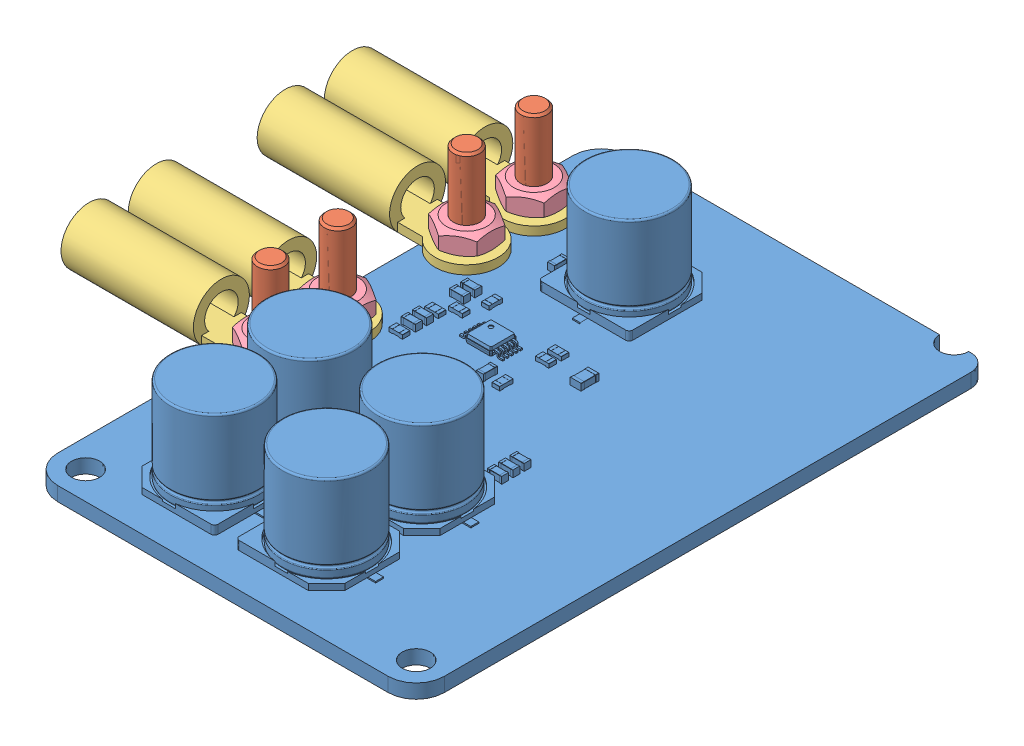
SolidWorks assembly Boost-Converter, configuration Standard. Lengths in mm.
Overall size (61.21 15.1 64.77).
13 component instances, 4 part files, 39 mates.
Components (placement in the parent):
- lt3757-boost-converter-1: lt3757-boost-converter [Standard] x (1 0 0) z (0 1 0) size (43.81 64.77 12.1)
- b-DIN EN ISO 4762-M3x12-1: b-DIN EN ISO 4762-M3x12 [Default] at (-18.7325 -1.6 -21.59) x (1 0 0) z (0 -1 0) size (5.5 5.5 15)
- b-DIN EN ISO 4762-M3x12-2: b-DIN EN ISO 4762-M3x12 [Default] at (-18.7325 -1.6 -13.97) x (1 0 0) z (0 -1 0) size (5.5 5.5 15)
- b-DIN EN ISO 4762-M3x12-3: b-DIN EN ISO 4762-M3x12 [Default] at (-18.7325 -1.6 0.635) x (1 0 0) z (0 -1 0) size (5.5 5.5 15)
- b-DIN EN ISO 4762-M3x12-4: b-DIN EN ISO 4762-M3x12 [Default] at (-18.7325 -1.6 8.255) x (1 0 0) z (0 -1 0) size (5.5 5.5 15)
- Cable-Lug_TE-2-34852-1-1: Cable-Lug_TE-2-34852-1 [Standard] at (-18.7325 0 -21.59) x (-1 0 0) z (0 0 -1) size (24.14 6.35 7.14)
- Cable-Lug_TE-2-34852-1-2: Cable-Lug_TE-2-34852-1 [Standard] at (-18.7325 0 -13.97) x (-1 0 0) z (0 0 -1) size (24.14 6.35 7.14)
- Cable-Lug_TE-2-34852-1-3: Cable-Lug_TE-2-34852-1 [Standard] at (-18.7325 0 0.635) x (-1 0 0) z (0 0 -1) size (24.14 6.35 7.14)
- Cable-Lug_TE-2-34852-1-4: Cable-Lug_TE-2-34852-1 [Standard] at (-18.7325 0 8.255) x (-1 0 0) z (0 0 -1) size (24.14 6.35 7.14)
- b-DIN EN ISO 4032-M3-1: b-DIN EN ISO 4032-M3 [Default] at (-18.7325 0.99 -21.59) x (0.866025 0 -0.5) z (0 1 0) size (6.35 5.5 2.4)
- b-DIN EN ISO 4032-M3-2: b-DIN EN ISO 4032-M3 [Default] at (-18.7325 0.99 -13.97) x (0.866025 0 -0.5) z (0 1 0) size (6.35 5.5 2.4)
- b-DIN EN ISO 4032-M3-3: b-DIN EN ISO 4032-M3 [Default] at (-18.7325 0.99 0.635) x (0.866025 0 -0.5) z (0 1 0) size (6.35 5.5 2.4)
- b-DIN EN ISO 4032-M3-4: b-DIN EN ISO 4032-M3 [Default] at (-18.7325 0.99 8.255) x (0.866025 0 -0.5) z (0 1 0) size (6.35 5.5 2.4)
Mates (geometry in assembly coordinates):
- Konzentrisch1: concentric anti-aligned: cylinder of lt3757-boost-converter-1 through (-18.7325 0 -21.59) axis (0 1 0) radius 1.6; cylinder of b-DIN EN ISO 4762-M3x12-1 through (-18.7325 -6.2001 -21.59) axis (0 -1 0) radius 1.5
- Konzentrisch2: concentric anti-aligned: cylinder of lt3757-boost-converter-1 through (-18.7325 0 -13.97) axis (0 1 0) radius 1.6; cylinder of b-DIN EN ISO 4762-M3x12-2 through (-18.7325 -6.2001 -13.97) axis (0 -1 0) radius 1.5
- Konzentrisch3: concentric anti-aligned: cylinder of lt3757-boost-converter-1 through (-18.7325 0 0.635) axis (0 1 0) radius 1.6; cylinder of b-DIN EN ISO 4762-M3x12-3 through (-18.7325 -6.2001 0.635) axis (0 -1 0) radius 1.5
- Konzentrisch4: concentric anti-aligned: cylinder of lt3757-boost-converter-1 through (-18.7325 0 8.255) axis (0 1 0) radius 1.6; cylinder of b-DIN EN ISO 4762-M3x12-4 through (-18.7325 -6.2001 8.255) axis (0 -1 0) radius 1.5
- Deckungsgleich2: coincident anti-aligned: plane of lt3757-boost-converter-1 through (21.9075 -1.6 -30.48) normal (0 -1 0); plane of b-DIN EN ISO 4762-M3x12-1 through (-18.7325 -1.6 -18.84) normal (0 1 0)
- Deckungsgleich3: coincident anti-aligned: plane of lt3757-boost-converter-1 through (21.9075 -1.6 -30.48) normal (0 -1 0); plane of b-DIN EN ISO 4762-M3x12-2 through (-18.7325 -1.6 -11.22) normal (0 1 0)
- Deckungsgleich4: coincident anti-aligned: plane of lt3757-boost-converter-1 through (21.9075 -1.6 -30.48) normal (0 -1 0); plane of b-DIN EN ISO 4762-M3x12-3 through (-18.7325 -1.6 3.385) normal (0 1 0)
- Deckungsgleich5: coincident anti-aligned: plane of lt3757-boost-converter-1 through (21.9075 -1.6 -30.48) normal (0 -1 0); plane of b-DIN EN ISO 4762-M3x12-4 through (-18.7325 -1.6 11.005) normal (0 1 0)
- Parallel1: parallel aligned: plane of b-DIN EN ISO 4762-M3x12-1; plane of b-DIN EN ISO 4762-M3x12-2
- Parallel2: parallel aligned: plane of b-DIN EN ISO 4762-M3x12-1; plane of b-DIN EN ISO 4762-M3x12-3
- Parallel3: parallel aligned: plane of b-DIN EN ISO 4762-M3x12-1; plane of b-DIN EN ISO 4762-M3x12-4
- Parallel4: parallel anti-aligned: plane of b-DIN EN ISO 4762-M3x12-1; plane of lt3757-boost-converter-1 through (-21.9075 0 -29.21) normal (-1 0 0)
- Konzentrisch5: concentric aligned: cylinder of b-DIN EN ISO 4762-M3x12-4 through (-18.7325 -6.2001 8.255) axis (0 -1 0) radius 1.5; cylinder of Cable-Lug_TE-2-34852-1-4 through (-18.7325 0.99 8.255) axis (0 -1 0) radius 1.84
- Konzentrisch6: concentric anti-aligned: cylinder of b-DIN EN ISO 4762-M3x12-3 through (-18.7325 -6.2001 0.635) axis (0 -1 0) radius 1.5; circle of Cable-Lug_TE-2-34852-1-3
- Konzentrisch7: concentric aligned: cylinder of b-DIN EN ISO 4762-M3x12-2 through (-18.7325 -6.2001 -13.97) axis (0 -1 0) radius 1.5; cylinder of Cable-Lug_TE-2-34852-1-2 through (-18.7325 0.99 -13.97) axis (0 -1 0) radius 1.84
- Konzentrisch8: concentric aligned: cylinder of b-DIN EN ISO 4762-M3x12-1 through (-18.7325 -6.2001 -21.59) axis (0 -1 0) radius 1.5; cylinder of Cable-Lug_TE-2-34852-1-1 through (-18.7325 0.99 -21.59) axis (0 -1 0) radius 1.84
- Deckungsgleich6: coincident anti-aligned: plane of lt3757-boost-converter-1 through (21.9075 0 -30.48) normal (0 1 0); plane of Cable-Lug_TE-2-34852-1-1 through (-18.7325 0 -21.59) normal (0 -1 0)
- Deckungsgleich7: coincident anti-aligned: plane of lt3757-boost-converter-1 through (21.9075 0 -30.48) normal (0 1 0); plane of Cable-Lug_TE-2-34852-1-2 through (-18.7325 0 -13.97) normal (0 -1 0)
- Deckungsgleich8: coincident anti-aligned: plane of lt3757-boost-converter-1 through (21.9075 0 -30.48) normal (0 1 0); plane of Cable-Lug_TE-2-34852-1-3 through (-18.7325 0 0.635) normal (0 -1 0)
- Deckungsgleich9: coincident anti-aligned: plane of lt3757-boost-converter-1 through (21.9075 0 -30.48) normal (0 1 0); plane of Cable-Lug_TE-2-34852-1-4 through (-18.7325 0 8.255) normal (0 -1 0)
- Parallel5: parallel aligned: plane of lt3757-boost-converter-1 through (-21.9075 0 -29.21) normal (-1 0 0); plane of Cable-Lug_TE-2-34852-1-1 through (-18.7325 0 -21.59) normal (-1 0 0)
- Parallel6: parallel aligned: plane of lt3757-boost-converter-1 through (-21.9075 0 -29.21) normal (-1 0 0); plane of Cable-Lug_TE-2-34852-1-2 through (-18.7325 0 -13.97) normal (-1 0 0)
- Parallel7: parallel aligned: plane of lt3757-boost-converter-1 through (-21.9075 0 -29.21) normal (-1 0 0); plane of Cable-Lug_TE-2-34852-1-3 through (-18.7325 0 0.635) normal (-1 0 0)
- Parallel8: parallel aligned: plane of lt3757-boost-converter-1 through (-21.9075 0 -29.21) normal (-1 0 0); plane of Cable-Lug_TE-2-34852-1-4 through (-18.7325 0 8.255) normal (-1 0 0)
- Konzentrisch9: concentric anti-aligned: cylinder of b-DIN EN ISO 4762-M3x12-1 through (-18.7325 -6.2001 -21.59) axis (0 -1 0) radius 1.5; cylinder of b-DIN EN ISO 4032-M3-1 through (-18.7325 3.39 -21.59) axis (0 1 0) radius 1.2294
- Konzentrisch10: concentric anti-aligned: cylinder of b-DIN EN ISO 4762-M3x12-2 through (-18.7325 -6.2001 -13.97) axis (0 -1 0) radius 1.5; cylinder of b-DIN EN ISO 4032-M3-2 through (-18.7325 3.39 -13.97) axis (0 1 0) radius 1.2294
- Konzentrisch11: concentric anti-aligned: cylinder of b-DIN EN ISO 4762-M3x12-3 through (-18.7325 -6.2001 0.635) axis (0 -1 0) radius 1.5; cylinder of b-DIN EN ISO 4032-M3-3 through (-18.7325 3.39 0.635) axis (0 1 0) radius 1.2294
- Konzentrisch12: concentric anti-aligned: cylinder of b-DIN EN ISO 4762-M3x12-4 through (-18.7325 -6.2001 8.255) axis (0 -1 0) radius 1.5; cylinder of b-DIN EN ISO 4032-M3-4 through (-18.7325 3.39 8.255) axis (0 1 0) radius 1.2294
- Deckungsgleich10: coincident anti-aligned: plane of Cable-Lug_TE-2-34852-1-1 through (-18.7325 0.99 -21.59) normal (0 1 0); plane of b-DIN EN ISO 4032-M3-1 through (-18.7325 0.99 -24.7654) normal (0 -1 0)
- Deckungsgleich11: coincident anti-aligned: plane of Cable-Lug_TE-2-34852-1-1 through (-18.7325 0.99 -21.59) normal (0 1 0); plane of b-DIN EN ISO 4032-M3-2 through (-18.7325 0.99 -17.1454) normal (0 -1 0)
- Deckungsgleich12: coincident anti-aligned: plane of Cable-Lug_TE-2-34852-1-1 through (-18.7325 0.99 -21.59) normal (0 1 0); plane of b-DIN EN ISO 4032-M3-3 through (-18.7325 0.99 -2.5404) normal (0 -1 0)
- Deckungsgleich13: coincident anti-aligned: plane of Cable-Lug_TE-2-34852-1-1 through (-18.7325 0.99 -21.59) normal (0 1 0); plane of b-DIN EN ISO 4032-M3-4 through (-18.7325 0.99 5.0796) normal (0 -1 0)
- Parallel9: parallel aligned: plane of lt3757-boost-converter-1 through (-21.9075 0 -29.21) normal (-1 0 0); plane of b-DIN EN ISO 4032-M3-1 through (-21.4825 0.99 -20.0023) normal (-1 0 0)
- Parallel10: parallel aligned: plane of lt3757-boost-converter-1 through (-21.9075 0 -29.21) normal (-1 0 0); plane of b-DIN EN ISO 4032-M3-2 through (-21.4825 0.99 -12.3823) normal (-1 0 0)
- Parallel11: parallel aligned: plane of lt3757-boost-converter-1 through (-21.9075 0 -29.21) normal (-1 0 0); plane of b-DIN EN ISO 4032-M3-3 through (-21.4825 0.99 2.2227) normal (-1 0 0)
- Parallel12: parallel aligned: plane of lt3757-boost-converter-1 through (-21.9075 0 -29.21) normal (-1 0 0); plane of b-DIN EN ISO 4032-M3-4 through (-21.4825 0.99 9.8427) normal (-1 0 0)
- Deckungsgleich14: coincident aligned: plane of lt3757-boost-converter-1 through (0 0 0) normal (0 1 0); plane of assembly
- Deckungsgleich15: coincident aligned: plane of lt3757-boost-converter-1; plane of assembly
- Deckungsgleich16: coincident anti-aligned: plane of lt3757-boost-converter-1 through (0 0 0) normal (0 0 -1); plane of assembly
